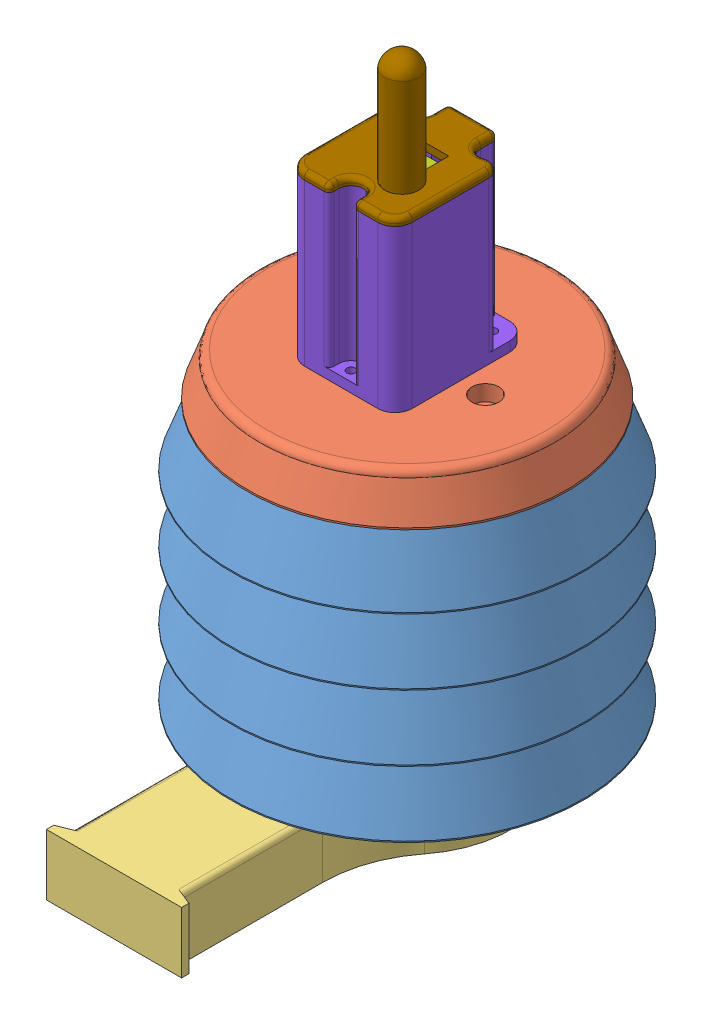
SolidWorks assembly modelo_prototipo, configuration Predeterminado. Lengths in mm.
Overall size (143.89 264.05 191.95).
13 component instances, 9 part files, 16 mates.
Components (placement in the parent):
- modulo_porta_componente-1: modulo_porta_componente [Predeterminado] at origin size (143.89 32 143.89)
- modulo_porta_componente-2: modulo_porta_componente [Predeterminado] at (0 54 0) size (143.89 32 143.89)
- modulo_porta_componente-3: modulo_porta_componente [Predeterminado] at (0 27 0) size (143.89 32 143.89)
- modulo_porta_componente-4: modulo_porta_componente [Predeterminado] at (0 81 0) size (143.89 32 143.89)
- Tapa_superior_con_ventana-1: Tapa_superior_con_ventana [Predeterminado] at origin size (130.72 17.78 130.72)
- carcasa_sup_base-1: carcasa_sup_base [Predeterminado] at (-22.6622 -55 0) x (0 0 1) z (-1 0 0) size (162.5 25 85)
- modulo_baliza_Lora-1: modulo_baliza_Lora [Predeterminado] at (28.085 4.5002 -25.1183) x (0 0 -1) z (1 0 0) size (54 118.05 44)
  - base_baliza_LDR_LoRa-1: base_baliza_LDR_LoRa [Predeterminado] at (-52.1183 86.4998 -6.085) size (54 62 44)
  - modulo_LoRa-1: modulo_LoRa [Predeterminado] at (-37.1183 153.6998 -10.085) x (0 -1 0) z (0 0 1) size (86.1 8 36)
  - tiraLedWS2812-1: tiraLedWS2812 [Predeterminado] at (-14.5683 91.4998 -35.785) x (0 1 0) z (1 0 0) size (57.2 10.7 3)
  - sensor LDR-1: sensor LDR [Predeterminado] at (-14.5683 148.6998 -16.585) x (0 0 -1) z (1 0 0) size (31.6 6.34 15)
  - carcasa_modulo_baliza-1: carcasa_modulo_baliza [Predeterminado] at origin size (54 66 44)
  - tapa_sup_antena-1: tapa_sup_antena [Predeterminado] at origin size (54 49.05 44)
Mates (geometry in assembly coordinates):
- Concéntrica1: concentric aligned: cylinder of modulo_porta_componente-1 through (-32 -30.001 0) axis (0 1 0) radius 3.5; cylinder of modulo_porta_componente-2 through (-32 23.999 0) axis (0 1 0) radius 3.5
- Concéntrica2: concentric aligned: cylinder of modulo_porta_componente-1 through (32 -30.001 0) axis (0 1 0) radius 3.5; cylinder of modulo_porta_componente-2 through (32 23.999 0) axis (0 1 0) radius 3.5
- Concéntrica3: concentric aligned: cylinder of modulo_porta_componente-2 through (32 23.999 0) axis (0 1 0) radius 3.5; cylinder of modulo_porta_componente-3 through (32 -3.001 0) axis (0 1 0) radius 3.5
- Concéntrica4: concentric aligned: cylinder of modulo_porta_componente-2 through (-32 23.999 0) axis (0 1 0) radius 3.5; cylinder of modulo_porta_componente-3 through (-32 -3.001 0) axis (0 1 0) radius 3.5
- Concéntrica5: concentric aligned: cylinder of modulo_porta_componente-2 through (-32 23.999 0) axis (0 1 0) radius 3.5; cylinder of modulo_porta_componente-4 through (-32 50.999 0) axis (0 1 0) radius 3.5
- Concéntrica6: concentric aligned: cylinder of modulo_porta_componente-2 through (32 23.999 0) axis (0 1 0) radius 3.5; cylinder of modulo_porta_componente-4 through (32 50.999 0) axis (0 1 0) radius 3.5
- Distancia2: distance = 25 mm anti-aligned: plane of modulo_porta_componente-4 through (0 81 0) normal (0 -1 0); plane of modulo_porta_componente-2 through (60.4813 56 0) normal (0 1 0)
- Coincidente4: coincident aligned: plane of modulo_porta_componente-1 through (0 0 0) normal (0 0 1); plane of assembly through (0 0 0) normal (0 0 1)
- Coincidente5: coincident anti-aligned: plane of modulo_porta_componente-1 through (0 0 0) normal (0 -1 0); plane of assembly through (0 0 0) normal (0 1 0)
- Coincidente6: coincident aligned: plane of modulo_porta_componente-1 through (0 0 0) normal (1 0 0); plane of assembly through (0 0 0) normal (1 0 0)
- Concéntrica7: concentric aligned: cylinder of modulo_porta_componente-1 through (32 -30.001 0) axis (0 1 0) radius 3.5; cylinder of carcasa_sup_base-1 through (32 -55.001 0) axis (0 1 0) radius 3.5
- Concéntrica8: concentric aligned: cylinder of modulo_porta_componente-1 through (-32 -30.001 0) axis (0 1 0) radius 3.5; cylinder of carcasa_sup_base-1 through (-32 -55.001 0) axis (0 1 0) radius 3.5
- Distancia1: distance = 30 mm anti-aligned: plane of modulo_porta_componente-1 through (0 0 0) normal (0 -1 0); plane of carcasa_sup_base-1 through (72.6622 -30 57.2403) normal (0 1 0)
- Ancho1: width anti-aligned: plane of Tapa_superior_con_ventana-1 through (22 91 20) normal (-1 0 0); plane of modulo_baliza_Lora-1/base_baliza_LDR_LoRa-1 through (-22 91 -20) normal (1 0 0); plane of Tapa_superior_con_ventana-1 through (22 94 20) normal (1 0 0); plane of modulo_baliza_Lora-1/base_baliza_LDR_LoRa-1 through (-22 94 20) normal (-1 0 0)
- Ancho2: width anti-aligned: plane of modulo_baliza_Lora-1/base_baliza_LDR_LoRa-1 through (15 94 -27) normal (0 0 -1); plane of Tapa_superior_con_ventana-1 through (15 94 27) normal (0 0 1); plane of modulo_baliza_Lora-1/base_baliza_LDR_LoRa-1 through (15 91 -27) normal (0 0 1); plane of Tapa_superior_con_ventana-1 through (-15 91 27) normal (0 0 -1)
- Coincidente7: coincident: plane of Tapa_superior_con_ventana-1 through (0 94 0) normal (0 1 0); line of modulo_baliza_Lora-1/carcasa_modulo_baliza-1 through (-22 94 -20) axis (0 0 1)
